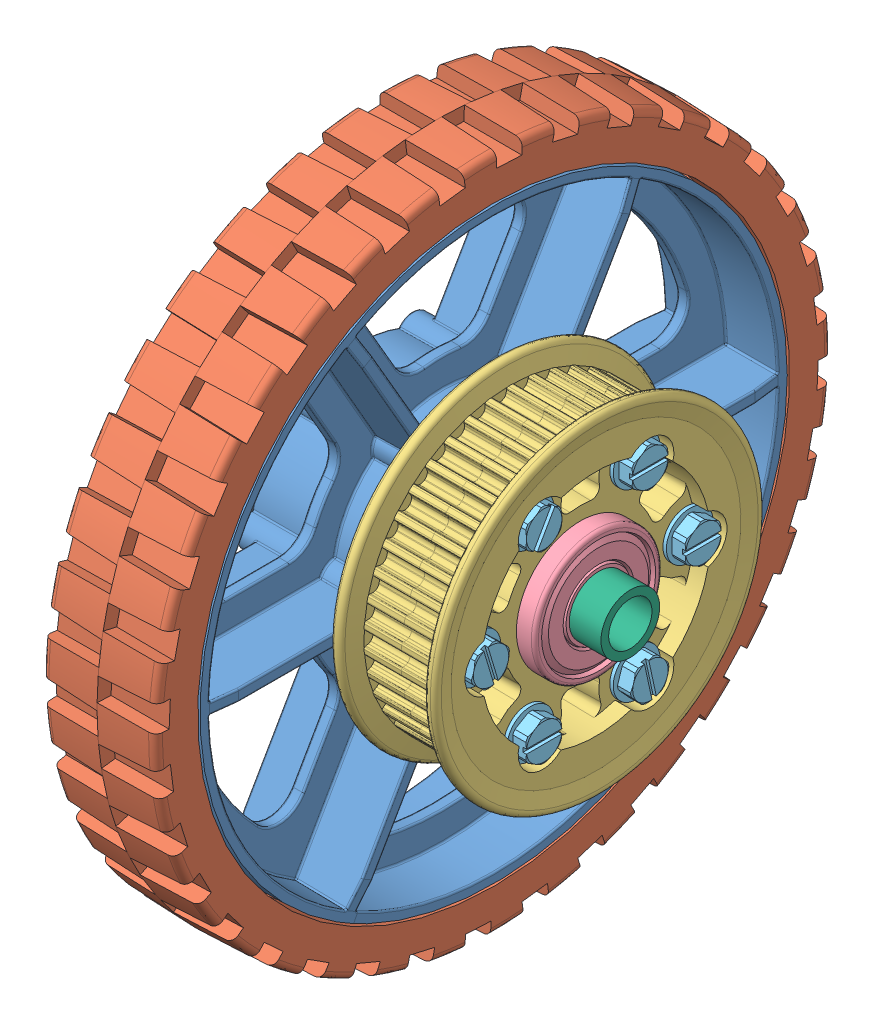
SolidWorks assembly Wheel-6inHiGrip_Outer, configuration Default. Lengths in mm.
Overall size (85.56 191.55 191.55).
15 component instances, 7 part files, 26 mates.
Components (placement in the parent):
- Wheel_6inHiGrip-1: Wheel_6inHiGrip [Default] at (83.7987 67.439 110.9939) size (35.05 191.55 191.55)
  - Wheel_6inHiGrip_Wheel-1: Wheel_6inHiGrip_Wheel [Default] at (-52.6446 9.4231 21.378) size (35.05 132.08 132.08)
  - Wheel_6inHiGrip_Tread-1: Wheel_6inHiGrip_Tread [Default] at (-65.3446 9.4231 21.378) x (0 -0.304368 -0.952555) z (1 0 0) size (152.4 152.4 25.58)
- HalfPulley_42t5mm-1: HalfPulley_42t5mm [Default] at (47.6006 76.862 132.3719) x (1 0 0) z (0 -0.5 0.866025) size (13 74.23 74.23)
- HalfPulley_42t5mm-2: HalfPulley_42t5mm [Default] at (64.263 76.862 132.3719) x (-1 0 0) z (0 -0.499927 0.866067) size (13 74.23 74.23)
- Bearing_1614ZZ-1: Bearing_1614ZZ [Default] at (62.612 76.862 132.3719) x (0 -0.157148 -0.987575) z (-1 0 0) size (28.57 28.57 9.53)
- Bearing_1614ZZ-2: Bearing_1614ZZ [Default] at (15.2791 76.862 132.3719) x (0 0 -1) z (1 0 0) size (28.57 28.57 9.53)
- ThreadFormingScrew_10-24x1.25-1: ThreadFormingScrew_10-24x1.25 [93882A213] at (63.247 76.8605 108.5602) x (0 0 -1) z (1 0 0) size (10.52 10.52 35.59)
- ThreadFormingScrew_10-24x1.25-2: ThreadFormingScrew_10-24x1.25 [93882A213] at (63.247 97.4833 120.4656) x (0 0 -1) z (1 0 0) size (10.52 10.52 35.59)
- ThreadFormingScrew_10-24x1.25-3: ThreadFormingScrew_10-24x1.25 [93882A213] at (63.247 56.2398 144.2799) x (0 0 -1) z (1 0 0) size (10.52 10.52 35.59)
- ThreadFormingScrew_10-24x1.25-4: ThreadFormingScrew_10-24x1.25 [93882A213] at (63.247 76.8625 156.1852) x (0 -0.95788 -0.287168) z (1 0 0) size (10.52 10.52 35.59)
- ThreadFormingScrew_10-24x1.25-5: ThreadFormingScrew_10-24x1.25 [93882A213] at (63.247 97.4843 144.2781) x (0 -0.868976 0.494854) z (1 0 0) size (10.52 10.52 35.59)
- ThreadFormingScrew_10-24x1.25-6: ThreadFormingScrew_10-24x1.25 [93882A213] at (63.247 56.2388 120.4674) x (0 -0.977348 -0.211637) z (1 0 0) size (10.52 10.52 35.59)
- Spacer_0.28x0.382-1: Spacer_0.28x0.382 [Default] at (74.4865 76.862 132.3719) x (0 -0.35357 0.935408) z (-1 0 0) size (13.16 13.16 7.11)
- Spacer_0.85x0.38-1: Spacer_0.85x0.38 [Default] at (-11.0734 76.862 132.3719) x (0 0 -1) z (1 0 0) size (19.05 19.05 21.59)
Mates (geometry in assembly coordinates):
- Concentric1: concentric anti-aligned: cylinder of Wheel_6inHiGrip-1/Wheel_6inHiGrip_Wheel-1 through (42.2666 76.862 132.3719) axis (1 0 0) radius 14.2875; cylinder of HalfPulley_42t5mm-1 through (54.0141 76.862 132.3719) axis (-1 0 0) radius 14.2875
- Coincident1: coincident anti-aligned: plane of Wheel_6inHiGrip-1/Wheel_6inHiGrip_Wheel-1 through (48.6166 76.862 132.3719) normal (1 0 0); plane of HalfPulley_42t5mm-1 through (48.6166 76.862 132.3719) normal (-1 0 0)
- Concentric4: concentric aligned: cylinder of HalfPulley_42t5mm-1 through (57.2018 56.2388 120.4674) axis (-1 0 0) radius 4.1275; cylinder of HalfPulley_42t5mm-2 through (57.3288 56.2388 120.4674) axis (-1 0 0) radius 4.1529
- Concentric5: concentric aligned: circle of HalfPulley_42t5mm-1; cylinder of HalfPulley_42t5mm-2 through (54.6618 97.4843 144.2781) axis (1 0 0) radius 4.1275
- Coincident2: coincident anti-aligned: plane of HalfPulley_42t5mm-1 through (55.9318 104.6844 148.5781) normal (1 0 0); plane of HalfPulley_42t5mm-2 through (55.9318 48.9145 116.3824) normal (-1 0 0)
- Concentric6: concentric anti-aligned: cylinder of HalfPulley_42t5mm-2 through (57.8495 76.862 132.3719) axis (1 0 0) radius 14.2875; cylinder of Bearing_1614ZZ-1 through (62.612 76.862 132.3719) axis (-1 0 0) radius 4.7625
- Concentric7: concentric anti-aligned: cylinder of Wheel_6inHiGrip-1/Wheel_6inHiGrip_Wheel-1 through (20.0416 76.862 132.3719) axis (-1 0 0) radius 14.2875; cylinder of Bearing_1614ZZ-2 through (15.2791 76.862 132.3719) axis (1 0 0) radius 4.7625
- Coincident3: coincident anti-aligned: plane of Wheel_6inHiGrip-1/Wheel_6inHiGrip_Wheel-1 through (20.0416 76.862 132.3719) normal (-1 0 0); plane of Bearing_1614ZZ-2 through (20.0416 76.862 132.3719) normal (1 0 0)
- Coincident4: coincident anti-aligned: plane of HalfPulley_42t5mm-2 through (57.8495 76.862 132.3719) normal (1 0 0); plane of Bearing_1614ZZ-1 through (57.8495 76.862 132.3719) normal (-1 0 0)
- Concentric8: concentric anti-aligned: cylinder of HalfPulley_42t5mm-2 through (55.9318 97.4833 120.4656) axis (1 0 0) radius 2.54; cylinder of ThreadFormingScrew_10-24x1.25-2 through (64.0141 97.4833 120.4656) axis (-1 0 0) radius 5.2578
- Concentric9: concentric anti-aligned: cylinder of HalfPulley_42t5mm-2 through (55.9318 76.8605 108.5602) axis (1 0 0) radius 2.54; circle of ThreadFormingScrew_10-24x1.25-1
- Concentric10: concentric anti-aligned: cylinder of HalfPulley_42t5mm-2 through (55.9318 56.2388 120.4674) axis (1 0 0) radius 2.54; cylinder of ThreadFormingScrew_10-24x1.25-6 through (64.0141 56.2388 120.4674) axis (-1 0 0) radius 5.2578
- Concentric11: concentric anti-aligned: cylinder of HalfPulley_42t5mm-2 through (55.9318 56.2398 144.2799) axis (1 0 0) radius 2.54; circle of ThreadFormingScrew_10-24x1.25-3
- Concentric12: concentric anti-aligned: cylinder of HalfPulley_42t5mm-2 through (55.9318 76.8625 156.1852) axis (1 0 0) radius 2.54; circle of ThreadFormingScrew_10-24x1.25-4
- Concentric13: concentric anti-aligned: cylinder of HalfPulley_42t5mm-2 through (55.9318 97.4843 144.2781) axis (1 0 0) radius 2.54; circle of ThreadFormingScrew_10-24x1.25-5
- Coincident5: coincident aligned: plane of ThreadFormingScrew_10-24x1.25-4 through (67.0824 78.1785 151.7955) normal (1 0 0); plane of ThreadFormingScrew_10-24x1.25-5 through (67.0824 95.2165 140.2958) normal (1 0 0)
- Coincident6: coincident aligned: plane of ThreadFormingScrew_10-24x1.25-3 through (67.0824 60.8225 144.2799) normal (1 0 0); plane of ThreadFormingScrew_10-24x1.25-4 through (67.0824 78.1785 151.7955) normal (1 0 0)
- Coincident7: coincident aligned: plane of ThreadFormingScrew_10-24x1.25-3 through (67.0824 60.8225 144.2799) normal (1 0 0); plane of ThreadFormingScrew_10-24x1.25-6 through (67.0824 57.2087 115.9884) normal (1 0 0)
- Coincident8: coincident aligned: plane of ThreadFormingScrew_10-24x1.25-1 through (67.0824 81.4433 108.5602) normal (1 0 0); plane of ThreadFormingScrew_10-24x1.25-6 through (67.0824 57.2087 115.9884) normal (1 0 0)
- Coincident9: coincident aligned: plane of ThreadFormingScrew_10-24x1.25-1 through (67.0824 81.4433 108.5602) normal (1 0 0); plane of ThreadFormingScrew_10-24x1.25-2 through (67.0824 102.066 120.4656) normal (1 0 0)
- Coincident10: coincident anti-aligned: plane of HalfPulley_42t5mm-2 through (63.247 76.862 132.3719) normal (1 0 0); plane of ThreadFormingScrew_10-24x1.25-5 through (63.247 95.2165 140.2958) normal (-1 0 0)
- Concentric14: concentric anti-aligned: cylinder of Bearing_1614ZZ-2 through (15.2791 76.862 132.3719) axis (1 0 0) radius 4.7625; cylinder of Spacer_0.85x0.38-1 through (10.5166 76.862 132.3719) axis (-1 0 0) radius 9.525
- Coincident11: coincident anti-aligned: plane of Bearing_1614ZZ-2 through (10.5166 76.862 132.3719) normal (-1 0 0); plane of Spacer_0.85x0.38-1 through (10.5166 76.862 132.3719) normal (1 0 0)
- Concentric15: concentric anti-aligned: cylinder of Bearing_1614ZZ-1 through (62.612 76.862 132.3719) axis (-1 0 0) radius 4.7625; cylinder of Spacer_0.28x0.382-1 through (67.3745 76.862 132.3719) axis (1 0 0) radius 4.8514
- Coincident12: coincident anti-aligned: plane of Bearing_1614ZZ-1 through (67.3745 76.862 132.3719) normal (1 0 0); plane of Spacer_0.28x0.382-1 through (67.3745 76.862 132.3719) normal (-1 0 0)
- Concentric16: concentric aligned: cylinder of Wheel_6inHiGrip-1/Wheel_6inHiGrip_Wheel-1 through (48.6166 97.4843 144.2781) axis (-1 0 0) radius 1.9939; cylinder of HalfPulley_42t5mm-1 through (55.9318 97.4843 144.2781) axis (-1 0 0) radius 2.54
